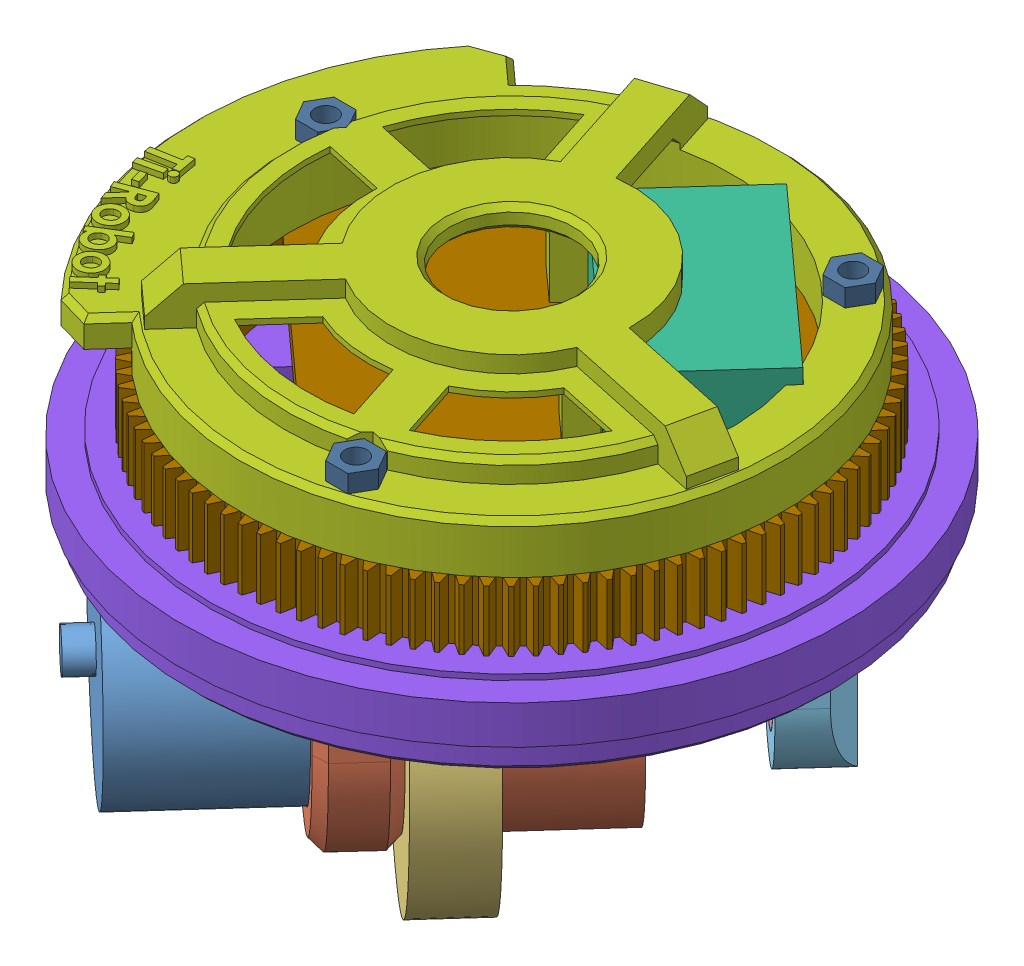
SolidWorks assembly steer, configuration ﾃﾞﾌｫﾙﾄ. Lengths in mm.
Overall size (169.48 100.92 169.48).
12 component instances, 10 part files, 28 mates.
Components (placement in the parent):
- Copy of M3508^steer-1: Copy of M3508^steer [ﾃﾞﾌｫﾙﾄ] at (107.8783 -47.57 102.4913) x (0 1 0) z (0.742238 0 0.670137) size (42 98.4 42) (virtual)
- Copy of motor_base^steer-1: Copy of motor_base^steer [ﾃﾞﾌｫﾙﾄ] at (107.8783 -47.57 102.4913) x (0 -1 0) z (0.670137 0 -0.742238) size (52 54 43) (virtual)
- Copy of bear_1^steer-1: Copy of bear_1^steer [ﾃﾞﾌｫﾙﾄ] at (50.5743 -31.5345 88.4776) x (-0.7341 0.147674 -0.662789) z (0.670137 0 -0.742238) size (72 72 12) (virtual)
- Copy of bear_2^steer-1: Copy of bear_2^steer [ﾃﾞﾌｫﾙﾄ] at (126.6421 -47.57 81.7086) x (0.245083 0.943913 0.221276) z (0.670137 0 -0.742238) size (26 26 8) (virtual)
- Copy of bear_cover^steer-1: Copy of bear_cover^steer [ﾃﾞﾌｫﾙﾄ] at (126.6421 -47.57 81.7086) x (0 -1 0) z (0.670137 0 -0.742238) size (43 40 11) (virtual)
- Copy of C620^steer-1: Copy of C620^steer [ﾃﾞﾌｫﾙﾄ] at (40.7118 -3.57 117.3762) x (0.670137 0 -0.742238) z (0 1 0) size (25.8 49.4 11.6) (virtual)
- Copy of striker^steer-1: Copy of striker^steer [ﾃﾞﾌｫﾙﾄ] at (99.1665 -3.57 112.1404) x (0.742238 0 0.670137) z (0 1 0) size (106.95 106.83 16) (virtual)
- Copy of steer_base^steer-1: Copy of steer_base^steer [ﾃﾞﾌｫﾙﾄ] at (99.1665 -22.57 112.1404) x (0.670137 0 -0.742238) z (0 1 0) size (120 120 13) (virtual)
- Copy of steer_gear_2^steer-1: Copy of steer_gear_2^steer [ﾃﾞﾌｫﾙﾄ] at (187.3107 -27.57 157.2026) x (-0.951474 0 0.307728) z (-0.307728 0 -0.951474) size (101.97 11 101.97) (virtual)
- Copy of M4_nut^steer-1: Copy of M4_nut^steer [ﾃﾞﾌｫﾙﾄ] at (128.6525 5.43 79.4819) x (1 0 0) z (0 1 0) size (8.08 7 3.2) (virtual)
- Copy of M4_nut^steer-2: Copy of M4_nut^steer [ﾃﾞﾌｫﾙﾄ] at (112.7065 5.43 154.0052) x (1 0 0) z (0 1 0) size (8.08 7 3.2) (virtual)
- Copy of M4_nut^steer-3: Copy of M4_nut^steer [ﾃﾞﾌｫﾙﾄ] at (56.1404 5.43 102.934) x (1 0 0) z (0 1 0) size (8.08 7 3.2) (virtual)
Mates (geometry in assembly coordinates):
- 同心円19: concentric anti-aligned: cylinder of Copy of M3508^Assem1_swerve_unit-1 through (126.173 -47.57 82.2282) axis (-0.670137 0 0.742238) radius 5; cylinder of Copy of bear_2^Assem1_swerve_unit-1 through (121.281 -47.57 87.6465) axis (0.670137 0 -0.742238) radius 5
- 同心円16: concentric anti-aligned: cylinder of Copy of motor_base^steer-1 through (81.0728 -47.57 132.1808) axis (0.670137 0 -0.742238) radius 25; cylinder of Copy of bear_1^Assem1_swerve_unit-1 through (97.1561 -47.57 114.3671) axis (-0.670137 0 0.742238) radius 25
- 距離1: distance = 50 mm anti-aligned: plane of Copy of motor_base^steer-1 through (87.7741 -47.57 124.7584) normal (0.670137 0 -0.742238); plane of Copy of bear_cover^Assem1_swerve_unit-1 through (121.281 -47.57 87.6465) normal (-0.670137 0 0.742238)
- 平行1: parallel aligned: plane of Copy of motor_base^steer-1 through (107.8146 -47.57 142.8521) normal (0.742238 0 0.670137); plane of Copy of bear_cover^Assem1_swerve_unit-1 through (142.0128 -22.57 91.5444) normal (0.742238 0 0.670137)
- 同心円21: concentric aligned: cylinder of Copy of bear_2^Assem1_swerve_unit-1 through (121.281 -47.57 87.6465) axis (0.670137 0 -0.742238) radius 13; cylinder of Copy of bear_cover^Assem1_swerve_unit-1 through (121.281 -47.57 87.6465) axis (0.670137 0 -0.742238) radius 13.15
- 一致52: coincident anti-aligned: plane of Copy of bear_2^Assem1_swerve_unit-1 through (126.6421 -47.57 81.7086) normal (0.670137 0 -0.742238); plane of Copy of bear_cover^Assem1_swerve_unit-1 through (126.6421 -47.57 81.7086) normal (-0.670137 0 0.742238)
- 同心円115: concentric aligned: cylinder of Copy of bear_cover^Assem1_swerve_unit-1 through (113.4981 -65.571 73.8833) axis (0 1 0) radius 2.25; cylinder of Copy of steer_base^Assem1_swerve_unit-1 through (113.4981 -25.57 73.8833) axis (0 1 0) radius 2.15
- 同心円116: concentric aligned: cylinder of Copy of bear_cover^Assem1_swerve_unit-1 through (135.7652 -65.571 93.9874) axis (0 1 0) radius 2.25; cylinder of Copy of steer_base^Assem1_swerve_unit-1 through (135.7652 -25.57 93.9874) axis (0 1 0) radius 2.15
- 一致234: coincident anti-aligned: plane of Copy of bear_cover^Assem1_swerve_unit-1 through (142.0128 -22.57 91.5444) normal (0 1 0); plane of Copy of steer_base^Assem1_swerve_unit-1 through (99.1665 -22.57 112.1404) normal (0 -1 0)
- 一致303: coincident anti-aligned: plane of Copy of C620^Assem1_swerve_unit-1 through (141.9348 8.03 101.6287) normal (0.670137 0 -0.742238); plane of Copy of striker^Assem1_swerve_unit-1 through (123.6016 -1.07 85.0763) normal (-0.670137 0 0.742238)
- 一致304: coincident anti-aligned: plane of Copy of C620^Assem1_swerve_unit-1 through (141.9348 8.03 101.6287) normal (0.742238 0 0.670137); plane of Copy of striker^Assem1_swerve_unit-1 through (117.4997 -1.07 128.6927) normal (-0.742238 0 -0.670137)
- 一致306: coincident aligned: plane of Copy of C620^Assem1_swerve_unit-1 through (40.7118 -3.57 117.3762) normal (0 -1 0); plane of Copy of striker^Assem1_swerve_unit-1 through (99.1665 -3.57 112.1404) normal (0 -1 0)
- 同心円113: concentric anti-aligned: cylinder of Copy of steer_gear_2^Assem1_swerve_unit-1 through (99.1665 -54.5701 112.1404) axis (0 1 0) radius 40; cylinder of Copy of striker^Assem1_swerve_unit-1 through (99.1665 5.43 112.1404) axis (0 -1 0) radius 40
- 同心円114: concentric anti-aligned: cylinder of Copy of steer_gear_2^Assem1_swerve_unit-1 through (128.6525 -14.57 79.4819) axis (0 1 0) radius 2.15; cylinder of Copy of striker^Assem1_swerve_unit-1 through (128.6525 5.43 79.4819) axis (0 -1 0) radius 2.15
- 同心円140: concentric anti-aligned: cylinder of Copy of striker^Assem1_swerve_unit-1 through (56.1404 5.43 102.934) axis (0 -1 0) radius 2.15; cylinder of Copy of steer_base^Assem1_swerve_unit-1 through (56.1404 -27.571 102.934) axis (0 1 0) radius 2.15
- 一致286: coincident anti-aligned: plane of Copy of striker^Assem1_swerve_unit-1 through (99.1665 5.43 112.1404) normal (0 1 0); plane of Copy of M4_nut^Assem1_swerve_unit-3 through (56.1404 5.43 102.934) normal (0 -1 0)
- 同心円155: concentric aligned: cylinder of Copy of striker^Assem1_swerve_unit-1 through (56.1404 5.43 102.934) axis (0 -1 0) radius 2.15; cylinder of Copy of M4_nut^Assem1_swerve_unit-3 through (56.1404 8.63 102.934) axis (0 -1 0) radius 2
- 一致287: coincident anti-aligned: plane of Copy of striker^Assem1_swerve_unit-1 through (99.1665 5.43 112.1404) normal (0 1 0); plane of Copy of M4_nut^Assem1_swerve_unit-1 through (128.6525 5.43 79.4819) normal (0 -1 0)
- 同心円156: concentric aligned: cylinder of Copy of striker^Assem1_swerve_unit-1 through (128.6525 5.43 79.4819) axis (0 -1 0) radius 2.15; cylinder of Copy of M4_nut^Assem1_swerve_unit-1 through (128.6525 8.63 79.4819) axis (0 -1 0) radius 2
- 一致288: coincident anti-aligned: plane of Copy of striker^Assem1_swerve_unit-1 through (99.1665 5.43 112.1404) normal (0 1 0); plane of Copy of M4_nut^Assem1_swerve_unit-2 through (112.7065 5.43 154.0052) normal (0 -1 0)
- 同心円157: concentric aligned: cylinder of Copy of striker^Assem1_swerve_unit-1 through (112.7065 5.43 154.0052) axis (0 -1 0) radius 2.15; cylinder of Copy of M4_nut^Assem1_swerve_unit-2 through (112.7065 8.63 154.0052) axis (0 -1 0) radius 2
- 一致300: coincident anti-aligned: plane of Copy of steer_gear_2^Assem1_swerve_unit-1 through (83.3147 -3.57 94.8022) normal (0 1 0); plane of Copy of striker^Assem1_swerve_unit-1 through (99.1665 -3.57 112.1404) normal (0 -1 0)
- 同心円129: concentric aligned: cylinder of Copy of steer_gear_2^Assem1_swerve_unit-1 through (99.1665 -54.5701 112.1404) axis (0 1 0) radius 40; circle of Copy of steer_base^Assem1_swerve_unit-1
- 一致251: coincident anti-aligned: plane of Copy of steer_gear_2^Assem1_swerve_unit-1 through (99.1665 -14.57 112.1404) normal (0 -1 0); plane of Copy of steer_base^Assem1_swerve_unit-1 through (99.1665 -14.57 112.1404) normal (0 1 0)
- 一致307: coincident anti-aligned: plane of Copy of motor_base^steer-1 through (87.7741 -22.57 124.7584) normal (0 1 0); plane of Copy of steer_base^steer-1 through (99.1665 -22.57 112.1404) normal (0 -1 0)
- 一致308: coincident anti-aligned: plane of Copy of M3508^steer-1 through (107.8783 -47.57 102.4913) normal (0.670137 0 -0.742238); plane of Copy of motor_base^steer-1 through (107.8783 -47.57 102.4913) normal (-0.670137 0 0.742238)
- 同心円158: concentric anti-aligned: cylinder of Copy of M3508^steer-1 through (89.9279 -56.32 99.7574) axis (0.670137 0 -0.742238) radius 2; cylinder of Copy of motor_base^steer-1 through (98.6397 -56.32 90.1083) axis (-0.670137 0 0.742238) radius 2.15
- 一致309: coincident anti-aligned: circle of Copy of motor_base^steer-1; plane of Copy of bear_1^steer-1 through (89.1144 -47.57 123.2739) normal (-0.670137 0 0.742238)
